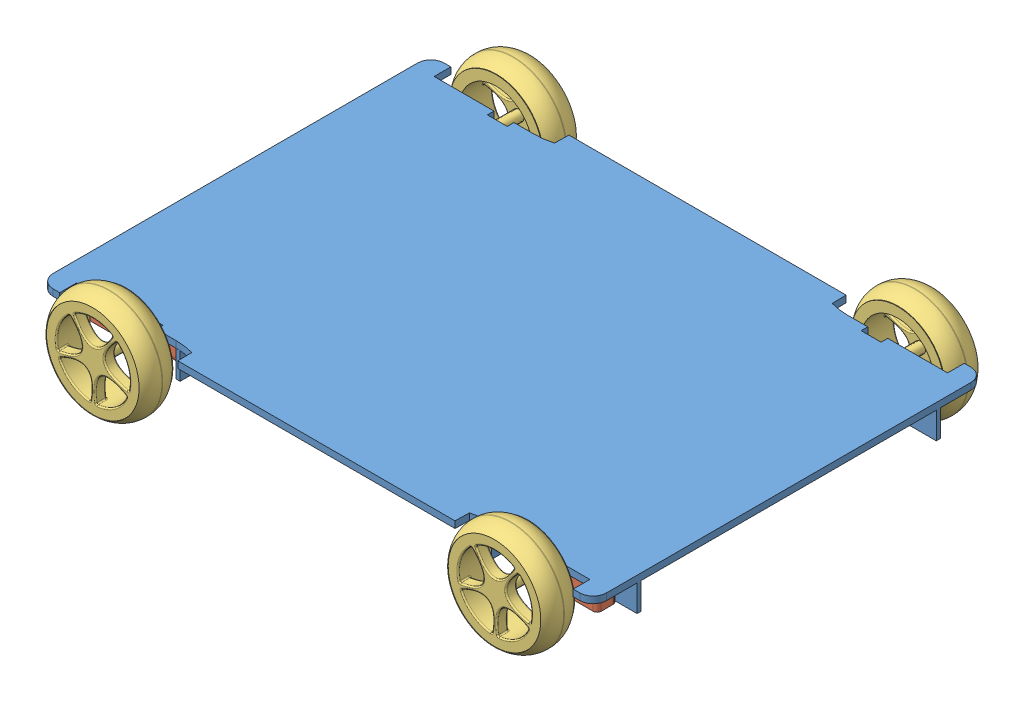
SolidWorks assembly Four_wheeled_base, configuration Predeterminado. Lengths in mm.
Overall size (832 160.02 657.43).
9 component instances, 3 part files, 20 mates.
Components (placement in the parent):
- Base-1: Base [Predeterminado] at (57.8294 19.1553 416) size (832 50 588)
- Coupler-1: Coupler [Predeterminado] at (-263.7651 -12.7989 659.0753) size (150 40 54)
- Wheel-1: Wheel [Predeterminado] at (-244.1709 -2.8078 732.2127) x (1 0 0) z (0 1 0) size (160 66.79 160)
- Coupler-2: Coupler [Predeterminado] at (-263.7651 7.2011 172.9243) x (1 0 0) z (0 0 -1) size (150 40 54)
- Coupler-3: Coupler [Predeterminado] at (379.4243 7.2011 659.0753) x (-1 0 0) z (0 0 1) size (150 40 54)
- Coupler-4: Coupler [Predeterminado] at (379.4243 -12.7989 172.9243) x (-1 0 0) z (0 0 -1) size (150 40 54)
- Wheel-2: Wheel [Predeterminado] at (-244.1709 -2.7901 99.7869) x (1 0 0) z (0 -1 0) size (160 66.79 160)
- Wheel-3: Wheel [Predeterminado] at (359.8291 -2.8078 732.2127) x (1 0 0) z (0 1 0) size (160 66.79 160)
- Wheel-4: Wheel [Predeterminado] at (359.8291 -2.7901 99.7869) x (1 0 0) z (0 -1 0) size (160 66.79 160)
Mates (geometry in assembly coordinates):
- Coincidente1: coincident anti-aligned: plane of Base-1 through (57.8296 17.2011 415.9998) normal (0 -1 0); plane of Coupler-1 through (-268.1704 17.2011 658.9198) normal (0 1 0)
- Coincidente2: coincident anti-aligned: plane of Base-1 through (-178.1704 -22.7989 643.9198) normal (0 0 1); plane of Coupler-1 through (-208.1704 17.2011 643.9198) normal (0 0 -1)
- Coincidente3: coincident anti-aligned: plane of Base-1 through (-208.1704 17.2011 674.9398) normal (-1 0 0); plane of Coupler-1 through (-208.1704 17.2011 673.9198) normal (1 0 0)
- Coincidente7: coincident anti-aligned: plane of Base-1 through (57.8296 17.2011 415.9998) normal (0 -1 0); plane of Coupler-2 through (-268.1704 17.2011 173.0798) normal (0 1 0)
- Coincidente8: coincident anti-aligned: plane of Base-1 through (-178.1704 -22.7989 188.0798) normal (0 0 -1); plane of Coupler-2 through (-208.1704 -22.7989 188.0798) normal (0 0 1)
- Coincidente9: coincident anti-aligned: plane of Base-1 through (-208.1704 17.2011 157.0598) normal (-1 0 0); plane of Coupler-2 through (-208.1704 -22.7989 158.0798) normal (1 0 0)
- Coincidente10: coincident anti-aligned: plane of Base-1 through (57.8296 17.2011 415.9998) normal (0 -1 0); plane of Coupler-4 through (383.8296 17.2011 173.0798) normal (0 1 0)
- Coincidente12: coincident anti-aligned: plane of Base-1 through (293.8296 -22.7989 188.0798) normal (0 0 -1); plane of Coupler-4 through (323.8296 17.2011 188.0798) normal (0 0 1)
- Coincidente13: coincident anti-aligned: plane of Base-1 through (323.8296 -22.7989 157.0598) normal (1 0 0); plane of Coupler-4 through (323.8296 17.2011 158.0798) normal (-1 0 0)
- Coincidente14: coincident anti-aligned: plane of Base-1 through (57.8296 17.2011 415.9998) normal (0 -1 0); plane of Coupler-3 through (175.8294 17.2011 658.9198) normal (0 1 0)
- Coincidente15: coincident anti-aligned: plane of Base-1 through (293.8296 -22.7989 643.9198) normal (0 0 1); plane of Coupler-3 through (115.8294 -22.7989 643.9198) normal (0 0 -1)
- Coincidente16: coincident anti-aligned: plane of Base-1 through (323.8296 -22.7989 674.9398) normal (1 0 0); plane of Coupler-3 through (115.8294 -22.7989 673.9198) normal (-1 0 0)
- Concéntrica1: concentric aligned: cylinder of Coupler-2 through (-244.1704 -2.7989 134.0798) axis (0 0 1) radius 5; axis of Wheel-2 through (-244.1704 -2.7989 134.0798) axis (0 0 1)
- Coincidente17: coincident anti-aligned: plane of Coupler-2 through (-244.1704 -2.7989 134.0798) normal (0 0 -1); plane of Wheel-2 through (-244.1704 -2.7989 134.0798) normal (0 0 1)
- Concéntrica2: concentric aligned: cylinder of Coupler-4 through (359.8296 -2.7989 134.0798) axis (0 0 1) radius 5; cylinder of Wheel-4 through (359.8296 -2.7989 134.0798) axis (0 0 1) radius 5
- Coincidente18: coincident anti-aligned: plane of Coupler-4 through (359.8296 -2.7989 134.0798) normal (0 0 -1); plane of Wheel-4 through (359.8296 -2.7989 134.0798) normal (0 0 1)
- Concéntrica3: concentric aligned: cylinder of Coupler-1 through (-244.1704 -2.7989 697.9198) axis (0 0 -1) radius 5; cylinder of Wheel-1 through (-244.1704 -2.7989 697.9198) axis (0 0 -1) radius 5
- Coincidente19: coincident anti-aligned: plane of Coupler-1 through (-244.1704 -2.7989 697.9198) normal (0 0 1); plane of Wheel-1 through (-244.1704 -2.7989 697.9198) normal (0 0 -1)
- Concéntrica4: concentric aligned: cylinder of Coupler-3 through (151.8294 -2.7989 697.9198) axis (0 0 -1) radius 5; cylinder of Wheel-3 through (151.8294 -2.7989 697.9198) axis (0 0 -1) radius 5
- Coincidente20: coincident anti-aligned: plane of Coupler-3 through (151.8294 -2.7989 697.9198) normal (0 0 1); plane of Wheel-3 through (151.8294 -2.7989 697.9198) normal (0 0 -1)
